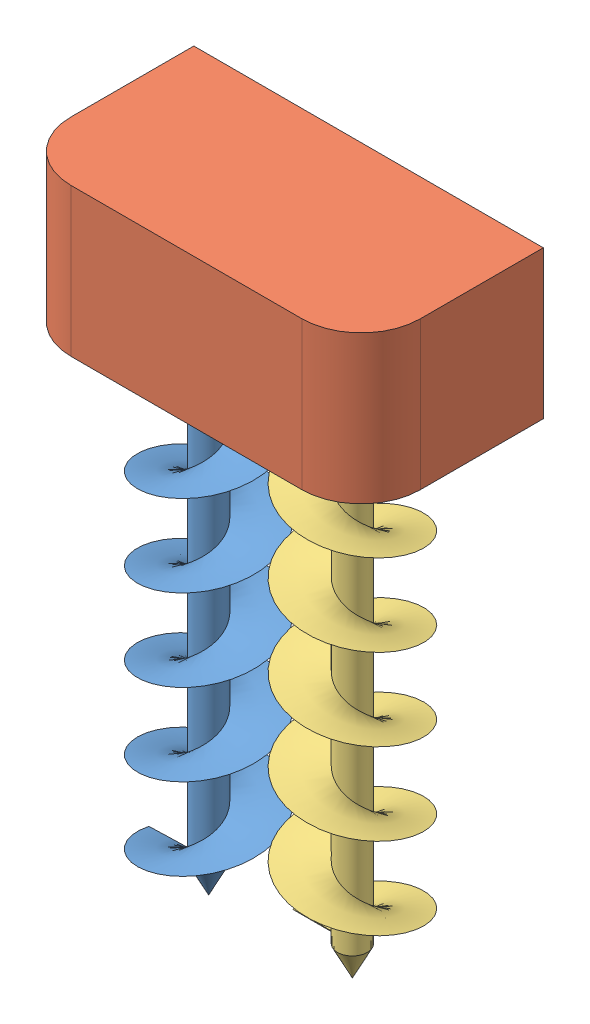
SolidWorks assembly fix, configuration Default. Lengths in mm.
Overall size (236 430 123).
3 component instances, 3 part files, 6 mates.
Components (placement in the parent):
- screw - Copy-1: screw - Copy [Default] at origin size (83 330 83)
- Part3^fix-1: Part3^fix [Default] at origin size (236 100 123) (virtual)
- screw2 - Copy - Copy-1: screw2 - Copy - Copy [Default] at (97.0846 0 0) size (83 330 83)
Mates (geometry in assembly coordinates):
- Coincident1: coincident: plane of Part3^fix-1 through (124.5 310 21.5) normal (0 -1 0); plane of ? through (206 310 0) normal (0 1 0)
- Parallel1: parallel: line of screw - Copy-1 through (-30 310 10) axis (1 0 0); line of ? through (176 310 10) axis (1 0 0)
- Distance1: distance = 0 mm: line of screw - Copy-1 through (-30 310 10) axis (1 0 0); line of ? through (68.0842 310 10) axis (1 0 0)
- Parallel2: parallel: line of screw - Copy-1 through (30 310 -10) axis (-1 0 0); line of screw2 - Copy - Copy-1 through (127.0846 310 -10) axis (-1 0 0)
- Distance2: distance = 0 mm: line of screw2 - Copy - Copy-1 through (127.0846 310 -10) axis (-1 0 0); line of screw - Copy-1 through (30 310 -10) axis (-1 0 0)
- Coincident2: coincident: plane of Part3^fix-1 through (124.5 310 21.5) normal (0 -1 0); plane of screw2 - Copy - Copy-1 through (97.0846 310 0) normal (0 1 0)
